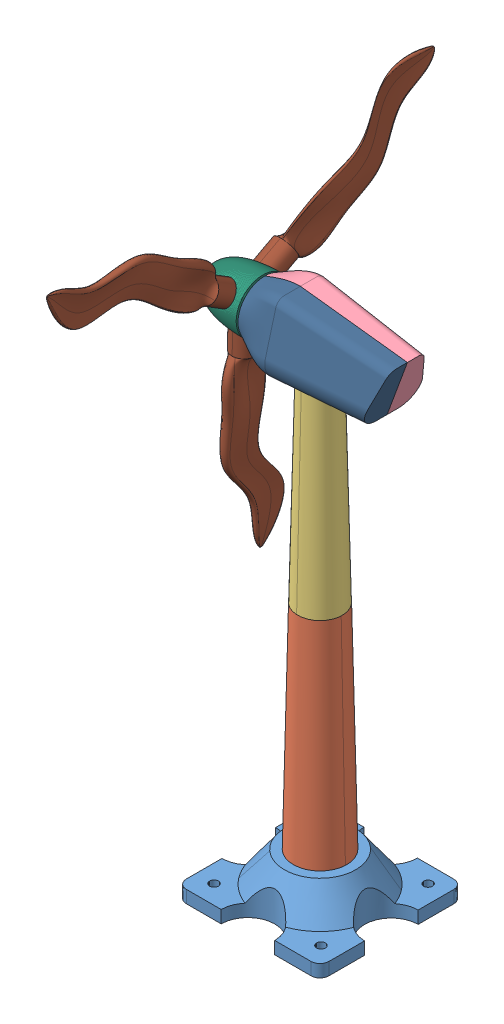
SolidWorks assembly Wind turbine assembly II (EXTERNAL RESULT) , configuration Default. Lengths in mm.
Overall size (140.98 456.4 306.35).
17 component instances, 11 part files, 0 mates.
Components (placement in the parent):
- Wind turbine assembly MARC2(cordinate).STEP-1: Wind turbine assembly MARC2(cordinate).STEP [Default] at origin size (140.98 456.4 306.35)
  - base.STEP-1: base.STEP [Default] at (78.4995 -345.44 -0.2668) x (-0.000714 0 1) z (-1 0 -0.000714) size (101.6 30.48 101.6)
  - Wind turbine lower mast.STEP-1: Wind turbine lower mast.STEP [Default] at (78.4995 -327.66 -0.2668) x (0 1 0) z (0.998658 0 0.051782) size (165.1 38.1 38.1)
  - Wind turbine upper mast.STEP-1: Wind turbine upper mast.STEP [Default] at (78.74 -175.26 0) x (0 1 0) z (-0.998658 0 -0.051782) size (152.4 31.75 31.75)
  - nacelle.STEP-1: nacelle.STEP [Default] at (64.77 0 0) x (0 0 1) z (-1 0 0) size (25.51 48.27 101.62)
  - connecting rod.STEP-1: connecting rod.STEP [Default] at (78.74 -29.21 0) x (-0.653528 0 0.756902) z (-0.756902 0 -0.653528) size (9.53 38.1 9.53)
  - Turbine Hub.STEP-1: Turbine Hub.STEP [Default] x (0 -0.031407 -0.999507) z (-1 0 0) size (41.13 38.1 38.1)
  - Turbine Hub.STEP-2: Turbine Hub.STEP [Default] x (0 0.881302 0.472554) z (-1 0 0) size (41.13 38.1 38.1)
  - Turbine Hub.STEP-3: Turbine Hub.STEP [Default] x (0 -0.849895 0.526953) z (-1 0 0) size (41.13 38.1 38.1)
  - 2780T350_HIGH-LOAD BEARING_2780T35.STEP-1: 2780T350_HIGH-LOAD BEARING_2780T35.STEP [Default] at (64.9287 0 0) x (0 0.911809 0.410615) z (-1 0 0) size (23.02 23.02 7.94)
  - 2780T350_HIGH-LOAD BEARING_2780T35.STEP-2: 2780T350_HIGH-LOAD BEARING_2780T35.STEP [Default] at (109.3787 0 0) x (0 -0.378851 0.925458) z (-1 0 0) size (23.02 23.02 7.94)
  - Turbine main shaft.STEP-1: Turbine main shaft.STEP [Default] at (73.025 0 0) x (0 -0.627713 -0.778445) z (0 -0.778445 0.627713) size (9.53 95.25 9.53)
  - 98408A134_SIDE-MOUNT EXTERNAL RETAINING RING  E-STYLE_98408A134.STEP-1: 98408A134_SIDE-MOUNT EXTERNAL RETAINING RING  E-STYLE_98408A134.STEP [Default] at (116.9919 0 0) size (0.89 16.76 15.36)
  - Mirrornacelle.STEP-1: Mirrornacelle.STEP [Default] at (64.77 0 0) x (0 0 -1) z (1 0 0) size (25.53 48.36 101.62)
  - rundwa wing(1).STEP-1: rundwa wing(1).STEP [Default] at (25.4 4.0154 6.4762) x (1 0 0) z (0 -0.849895 0.526953) size (19.03 151.58 60.38)
  - rundwa wing(1).STEP-2: rundwa wing(1).STEP [Default] at (25.4 3.6009 -6.7155) x (1 0 0) z (0 0.881302 0.472554) size (19.03 151.58 60.38)
  - rundwa wing(1).STEP-3: rundwa wing(1).STEP [Default] at (25.4 -7.6162 0.2393) x (1 0 0) z (0 -0.031407 -0.999507) size (19.03 151.58 60.38)
